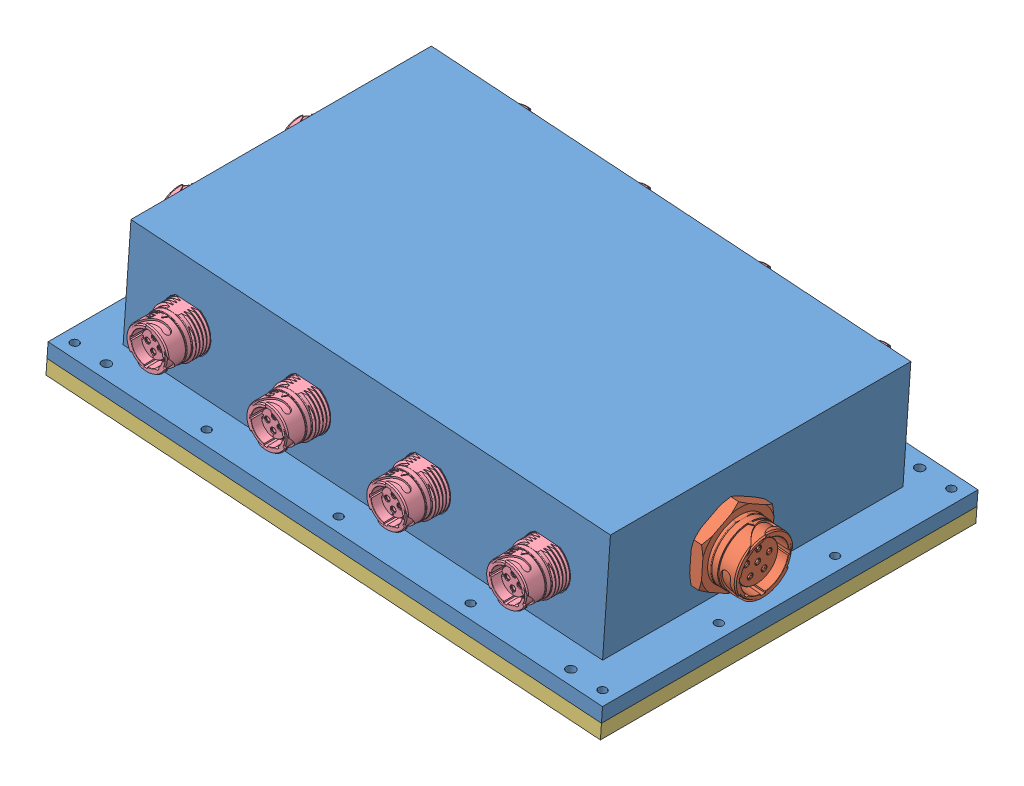
SolidWorks assembly Power Distribution Box Assembly, configuration Default. Lengths in mm.
Overall size (238.8 76.57 161.39).
13 component instances, 4 part files, 36 mates.
Components (placement in the parent):
- Power Distribution Box & connector holes v1-1: Power Distribution Box & connector holes v1 [Default] at (68.8696 153.9223 199.977) x (-0.997564 0.069756 0) z (0 0 1) size (234.95 53.98 158.75)
- Samtec ACR 22-3: Samtec ACR 22 [Default] at (184.6089 117.1842 212.677) x (0 0 -1) z (0.997564 -0.069756 0) size (38.11 34.64 24.46)
- EDB Lid-1: EDB Lid [Default] at (64.6616 93.7442 199.977) x (0.997564 -0.069756 0) z (0 0 1) size (234.95 6.35 158.75)
- Samtec ACR 16 Recepticle-1: Samtec ACR 16 Recepticle [Default] at (143.1122 123.2687 119.652) x (-0.997564 0.069756 0) z (0 0 -1) size (30.02 26 24.37)
- Samtec ACR 16 Recepticle-2: Samtec ACR 16 Recepticle [Default] at (92.436 126.8123 119.652) x (-0.997564 0.069756 0) z (0 0 -1) size (30.02 26 24.37)
- Samtec ACR 16 Recepticle-3: Samtec ACR 16 Recepticle [Default] at (41.7597 130.356 119.652) x (-0.997564 0.069756 0) z (0 0 -1) size (30.02 26 24.37)
- Samtec ACR 16 Recepticle-4: Samtec ACR 16 Recepticle [Default] at (-8.9166 133.8996 119.652) x (-0.997564 0.069756 0) z (0 0 -1) size (30.02 26 24.37)
- Samtec ACR 16 Recepticle-7: Samtec ACR 16 Recepticle [Default] at (-51.0387 136.8451 174.577) x (0 0 1) z (-0.997564 0.069756 0) size (30.02 26 24.37)
- Samtec ACR 16 Recepticle-8: Samtec ACR 16 Recepticle [Default] at (-51.0387 136.8451 225.377) x (0 0 1) z (-0.997564 0.069756 0) size (30.02 26 24.37)
- Samtec ACR 16 Recepticle-10: Samtec ACR 16 Recepticle [Default] at (-8.9166 133.8996 280.302) x (0.997564 -0.069756 0) z (0 0 1) size (30.02 26 24.37)
- Samtec ACR 16 Recepticle-11: Samtec ACR 16 Recepticle [Default] at (41.7597 130.356 280.302) x (0.997564 -0.069756 0) z (0 0 1) size (30.02 26 24.37)
- Samtec ACR 16 Recepticle-12: Samtec ACR 16 Recepticle [Default] at (92.436 126.8123 280.302) x (0.997564 -0.069756 0) z (0 0 1) size (30.02 26 24.37)
- Samtec ACR 16 Recepticle-13: Samtec ACR 16 Recepticle [Default] at (143.1122 123.2687 280.302) x (0.997564 -0.069756 0) z (0 0 1) size (30.02 26 24.37)
Mates (geometry in assembly coordinates):
- Coincident50: coincident anti-aligned: plane of Power Distribution Box & connector holes v1-1 through (166.457 92.9915 263.477) normal (0.997564 -0.069756 0); plane of Samtec ACR 22-3 through (168.2289 118.3296 212.677) normal (-0.997564 0.069756 0)
- Concentric32: concentric anti-aligned: circle of Power Distribution Box & connector holes v1-1; cylinder of Samtec ACR 22-3 through (184.6089 117.1842 212.677) axis (-0.997564 0.069756 0) radius 12.25
- Parallel30: parallel: line of Power Distribution Box & connector holes v1-1 through (166.9 99.326 136.477) axis (0.069756 0.997564 0); plane of Samtec ACR 22-3 through (167.6247 109.6905 197.677) normal (0 0 -1)
- Coincident84: coincident anti-aligned: plane of Power Distribution Box & connector holes v1-1 through (65.1045 100.0788 199.977) normal (-0.069756 -0.997564 0); plane of EDB Lid-1 through (65.1045 100.0788 199.977) normal (0.069756 0.997564 0)
- Concentric35: concentric aligned: cylinder of Power Distribution Box & connector holes v1-1 through (143.1122 123.2687 120.602) axis (0 0 1) radius 10.2489; cylinder of Samtec ACR 16 Recepticle-1 through (143.1122 123.2687 119.652) axis (0 0 1) radius 8.75
- Parallel31: parallel anti-aligned: plane of Power Distribution Box & connector holes v1-1 through (67.7073 137.3005 120.602) normal (-0.069756 -0.997564 0); plane of Samtec ACR 16 Recepticle-1 through (148.2695 131.6794 119.2818) normal (0.069756 0.997564 0)
- Tangent1: tangent: plane of Power Distribution Box & connector holes v1-1 through (-13.2101 391.1073 139.652) normal (0 0 1); torus of Samtec ACR 16 Recepticle-1
- Concentric36: concentric aligned: cylinder of Power Distribution Box & connector holes v1-1 through (92.436 126.8123 120.602) axis (0 0 1) radius 10.2489; cylinder of Samtec ACR 16 Recepticle-2 through (92.436 126.8123 119.652) axis (0 0 1) radius 8.75
- Tangent2: tangent: plane of Power Distribution Box & connector holes v1-1 through (-13.2101 391.1073 139.652) normal (0 0 1); torus of Samtec ACR 16 Recepticle-2
- Parallel32: parallel anti-aligned: plane of Power Distribution Box & connector holes v1-1 through (67.7073 137.3005 120.602) normal (-0.069756 -0.997564 0); plane of Samtec ACR 16 Recepticle-2 through (97.5932 135.2231 119.2818) normal (0.069756 0.997564 0)
- Tangent3: tangent: plane of Power Distribution Box & connector holes v1-1 through (-13.2101 391.1073 139.652) normal (0 0 1); torus of Samtec ACR 16 Recepticle-3
- Concentric37: concentric aligned: cylinder of Power Distribution Box & connector holes v1-1 through (41.7597 130.356 120.602) axis (0 0 1) radius 10.2489; cylinder of Samtec ACR 16 Recepticle-3 through (41.7597 130.356 119.652) axis (0 0 1) radius 8.75
- Parallel33: parallel anti-aligned: plane of Power Distribution Box & connector holes v1-1 through (67.7073 137.3005 120.602) normal (-0.069756 -0.997564 0); plane of Samtec ACR 16 Recepticle-3 through (46.917 138.7667 119.2818) normal (0.069756 0.997564 0)
- Tangent4: tangent: plane of Power Distribution Box & connector holes v1-1 through (-13.2101 391.1073 139.652) normal (0 0 1); torus of Samtec ACR 16 Recepticle-4
- Concentric38: concentric aligned: cylinder of Power Distribution Box & connector holes v1-1 through (-8.9166 133.8996 120.602) axis (0 0 1) radius 10.2489; cylinder of Samtec ACR 16 Recepticle-4 through (-8.9166 133.8996 119.652) axis (0 0 1) radius 8.75
- Parallel34: parallel anti-aligned: plane of Power Distribution Box & connector holes v1-1 through (67.7073 137.3005 120.602) normal (-0.069756 -0.997564 0); plane of Samtec ACR 16 Recepticle-4 through (-3.7593 142.3103 119.2818) normal (0.069756 0.997564 0)
- Concentric40: concentric anti-aligned: cylinder of Power Distribution Box & connector holes v1-1 through (184.2877 120.3894 174.577) axis (-0.997564 0.069756 0) radius 10.2489; cylinder of Samtec ACR 16 Recepticle-7 through (-51.0387 136.8451 174.577) axis (0.997564 -0.069756 0) radius 8.75
- Parallel35: parallel anti-aligned: plane of Power Distribution Box & connector holes v1-1 through (184.8972 129.1058 199.977) normal (-0.069756 -0.997564 0); plane of Samtec ACR 16 Recepticle-7 through (-50.7977 145.5996 170.019) normal (0.069756 0.997564 0)
- Tangent7: tangent: plane of Power Distribution Box & connector holes v1-1 through (-13.2101 391.1073 260.302) normal (0.997564 -0.069756 0); torus of Samtec ACR 16 Recepticle-7
- Concentric41: concentric anti-aligned: cylinder of Power Distribution Box & connector holes v1-1 through (184.2877 120.3894 225.377) axis (-0.997564 0.069756 0) radius 10.2489; cylinder of Samtec ACR 16 Recepticle-8 through (-51.0387 136.8451 225.377) axis (0.997564 -0.069756 0) radius 8.75
- Parallel36: parallel anti-aligned: plane of Power Distribution Box & connector holes v1-1 through (184.8972 129.1058 199.977) normal (-0.069756 -0.997564 0); plane of Samtec ACR 16 Recepticle-8 through (-50.7977 145.5996 220.819) normal (0.069756 0.997564 0)
- Tangent8: tangent: plane of Power Distribution Box & connector holes v1-1 through (-13.2101 391.1073 260.302) normal (0.997564 -0.069756 0); torus of Samtec ACR 16 Recepticle-8
- Concentric42: concentric anti-aligned: cylinder of Power Distribution Box & connector holes v1-1 through (-8.9166 133.8996 120.602) axis (0 0 1) radius 10.2489; cylinder of Samtec ACR 16 Recepticle-10 through (-8.9166 133.8996 280.302) axis (0 0 -1) radius 8.75
- Parallel37: parallel anti-aligned: plane of Power Distribution Box & connector holes v1-1 through (67.7073 137.3005 120.602) normal (-0.069756 -0.997564 0); plane of Samtec ACR 16 Recepticle-10 through (-12.8531 142.9462 280.6723) normal (0.069756 0.997564 0)
- Tangent9: tangent: plane of Power Distribution Box & connector holes v1-1 through (183.1604 377.3757 260.302) normal (0 0 -1); torus of Samtec ACR 16 Recepticle-10
- Concentric43: concentric anti-aligned: cylinder of Power Distribution Box & connector holes v1-1 through (41.7597 130.356 120.602) axis (0 0 1) radius 10.2489; cylinder of Samtec ACR 16 Recepticle-11 through (41.7597 130.356 280.302) axis (0 0 -1) radius 8.75
- Parallel38: parallel anti-aligned: plane of Power Distribution Box & connector holes v1-1 through (67.7073 137.3005 120.602) normal (-0.069756 -0.997564 0); plane of Samtec ACR 16 Recepticle-11 through (37.8232 139.4026 280.6723) normal (0.069756 0.997564 0)
- Tangent10: tangent: plane of Power Distribution Box & connector holes v1-1 through (183.1604 377.3757 260.302) normal (0 0 -1); torus of Samtec ACR 16 Recepticle-11
- Tangent11: tangent: plane of Power Distribution Box & connector holes v1-1 through (183.1604 377.3757 260.302) normal (0 0 -1); torus of Samtec ACR 16 Recepticle-12
- Concentric44: concentric anti-aligned: cylinder of Power Distribution Box & connector holes v1-1 through (92.436 126.8123 120.602) axis (0 0 1) radius 10.2489; cylinder of Samtec ACR 16 Recepticle-12 through (92.436 126.8123 280.302) axis (0 0 -1) radius 8.75
- Parallel39: parallel anti-aligned: plane of Power Distribution Box & connector holes v1-1 through (67.7073 137.3005 120.602) normal (-0.069756 -0.997564 0); plane of Samtec ACR 16 Recepticle-12 through (88.4994 135.859 280.6723) normal (0.069756 0.997564 0)
- Tangent12: tangent: plane of Power Distribution Box & connector holes v1-1 through (183.1604 377.3757 260.302) normal (0 0 -1); torus of Samtec ACR 16 Recepticle-13
- Concentric45: concentric anti-aligned: cylinder of Power Distribution Box & connector holes v1-1 through (143.1122 123.2687 120.602) axis (0 0 1) radius 10.2489; cylinder of Samtec ACR 16 Recepticle-13 through (143.1122 123.2687 280.302) axis (0 0 -1) radius 8.75
- Parallel40: parallel anti-aligned: plane of Power Distribution Box & connector holes v1-1 through (67.7073 137.3005 120.602) normal (-0.069756 -0.997564 0); plane of Samtec ACR 16 Recepticle-13 through (139.1757 132.3153 280.6723) normal (0.069756 0.997564 0)
- Concentric46: concentric anti-aligned: cylinder of Power Distribution Box & connector holes v1-1 through (176.681 92.2766 273.7259) axis (-0.069756 -0.997564 0) radius 1.7272; cylinder of EDB Lid-1 through (176.681 92.2766 273.7259) axis (0.069756 0.997564 0) radius 2.2479
- Coincident85: coincident aligned: plane of Power Distribution Box & connector holes v1-1 through (182.7363 98.2186 120.602) normal (0.997564 -0.069756 0); plane of EDB Lid-1 through (182.2934 91.8841 120.602) normal (0.997564 -0.069756 0)
